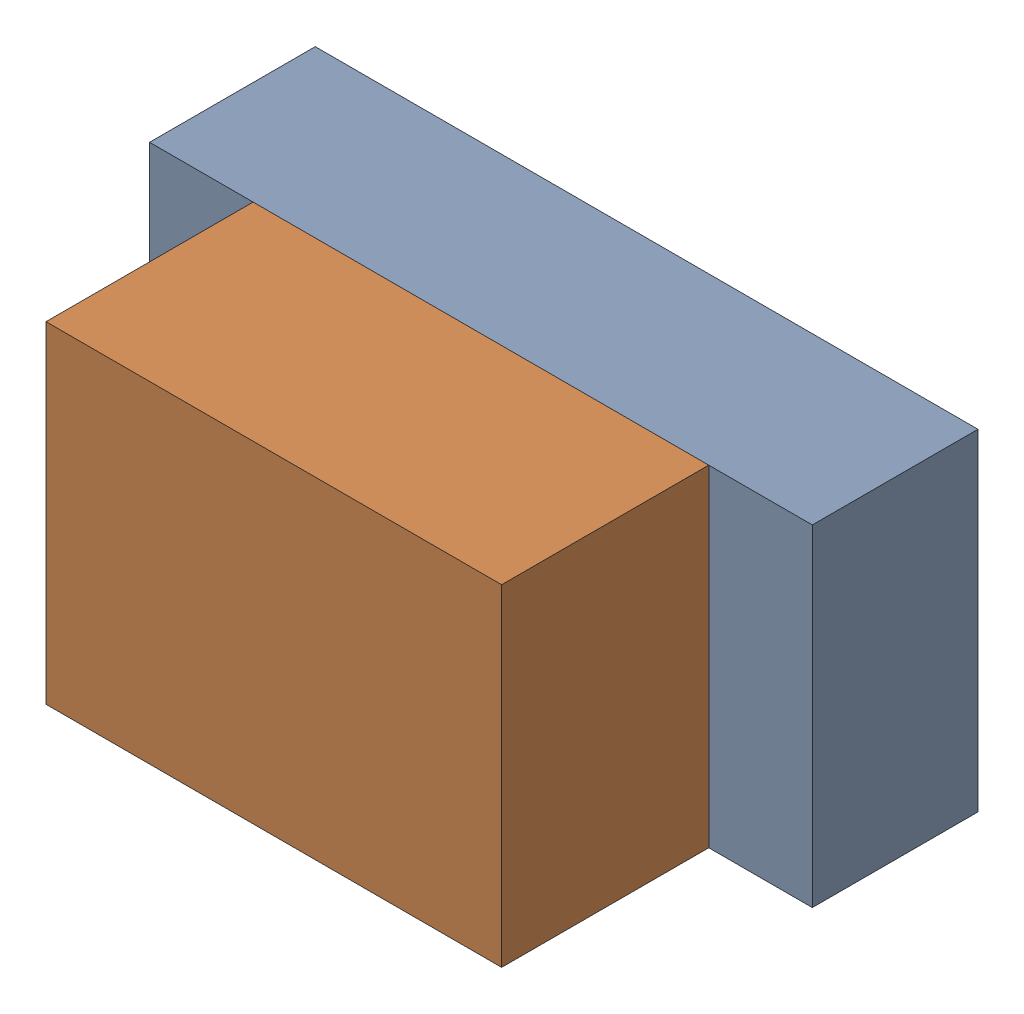
SolidWorks assembly LED2.step, configuration Default. Lengths in mm.
Overall size (1.6 0.8 0.9).
4 component instances, 2 part files, 0 mates.
Components (placement in the parent):
- 5958430896.step-1: 5958430896.step [Default] at (43.8149 64.6429 0) size (1.6 0.8 0.4)
  - Extruded.step-1: Extruded.step [Default] at origin size (1.6 0.8 0.4)
- 5958430656.step-1: 5958430656.step [Default] at (43.8149 64.6429 0.4) size (1.1 0.8 0.5)
  - Extruded-3.step-1: Extruded-3.step [Default] at origin size (1.1 0.8 0.5)
